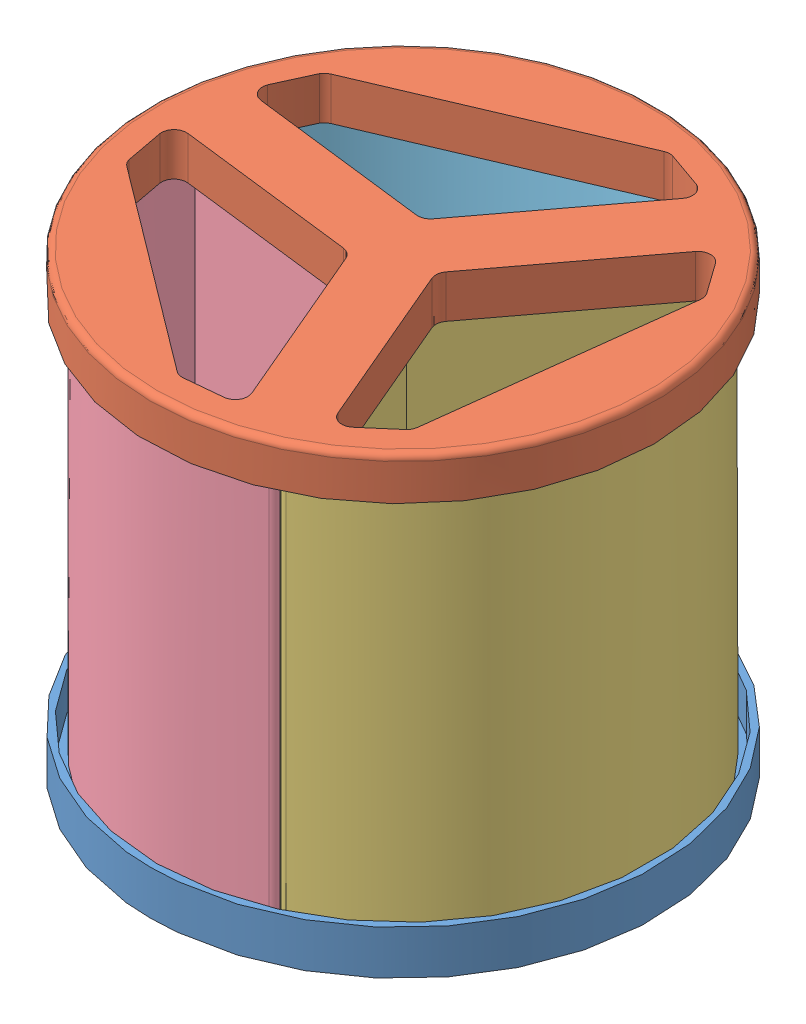
SolidWorks assembly Montagem1, configuration Valor predeterminado. Lengths in mm.
Overall size (524.74 360 524.74).
5 component instances, 5 part files, 11 mates.
Components (placement in the parent):
- Peça3-1: Peça3 [Valor predeterminado] at (20.5071 -99.9192 0) size (400 35 400)
- tampa-1: tampa [Valor predeterminado] at (20.5071 226.0808 0) x (-0.920047 0 0.391807) z (0 1 0) size (400 400 34)
- Peça6-1: Peça6 [Valor predeterminado] at (20.5071 -94.9192 0) x (0.992715 0 0.120485) z (-0.120485 0 0.992715) size (187.23 352.65 321.85)
- Peça7-1: Peça7 [Valor predeterminado] at (20.5071 -94.9192 0) x (-0.6007 0 0.799474) z (-0.799474 0 -0.6007) size (187.23 352.65 321.85)
- Peça5-1: Peça5 [Valor predeterminado] at (20.5071 -94.9192 0) x (-0.391268 0 -0.920277) z (0.920277 0 -0.391268) size (187.23 352.65 321.85)
Mates (geometry in assembly coordinates):
- Paralelo1: parallel anti-aligned: plane of Peça3-1 through (20.5071 -94.9192 0) normal (0 1 0); plane of Peça6-1 through (20.5071 -94.9192 0) normal (0 -1 0)
- Coincidente2: coincident anti-aligned: plane of Peça3-1 through (20.5071 -94.9192 0) normal (0 1 0); plane of Peça6-1 through (20.5071 -94.9192 0) normal (0 -1 0)
- Concêntrico4: concentric aligned: circle of Peça3-1; circle of Peça6-1
- Coincidente5: coincident anti-aligned: plane of Peça3-1 through (20.5071 -94.9192 0) normal (0 1 0); plane of Peça7-1 through (20.5071 -94.9192 0) normal (0 -1 0)
- Coincidente6: coincident anti-aligned: plane of Peça6-1 through (20.5071 257.0808 0) normal (-0.920047 0 0.391807); plane of Peça7-1 through (20.5071 257.0808 0) normal (0.920047 0 -0.391807)
- Concêntrico5: concentric aligned: circle of Peça3-1; circle of Peça7-1
- Coincidente9: coincident anti-aligned: plane of Peça3-1 through (20.5071 -94.9192 0) normal (0 1 0); plane of Peça5-1 through (20.5071 -94.9192 0) normal (0 -1 0)
- Concêntrico7: concentric aligned: circle of Peça3-1; circle of Peça5-1
- Coincidente11: coincident: plane of tampa-1 through (-616.5526 257.0808 95.6201) normal (0 -1 0); line of Peça7-1 through (90.2218 257.0808 171.3618) axis (-0.391807 0 -0.920047)
- Paralelo4: parallel aligned: plane of tampa-1 through (50.3098 226.0808 3.6239) normal (0.920047 0 -0.391807); plane of Peça6-1 through (23.2673 257.0808 -1.1754) normal (0.920047 0 -0.391807)
- Concêntrico9: concentric aligned: circle of tampa-1; circle of Peça5-1
